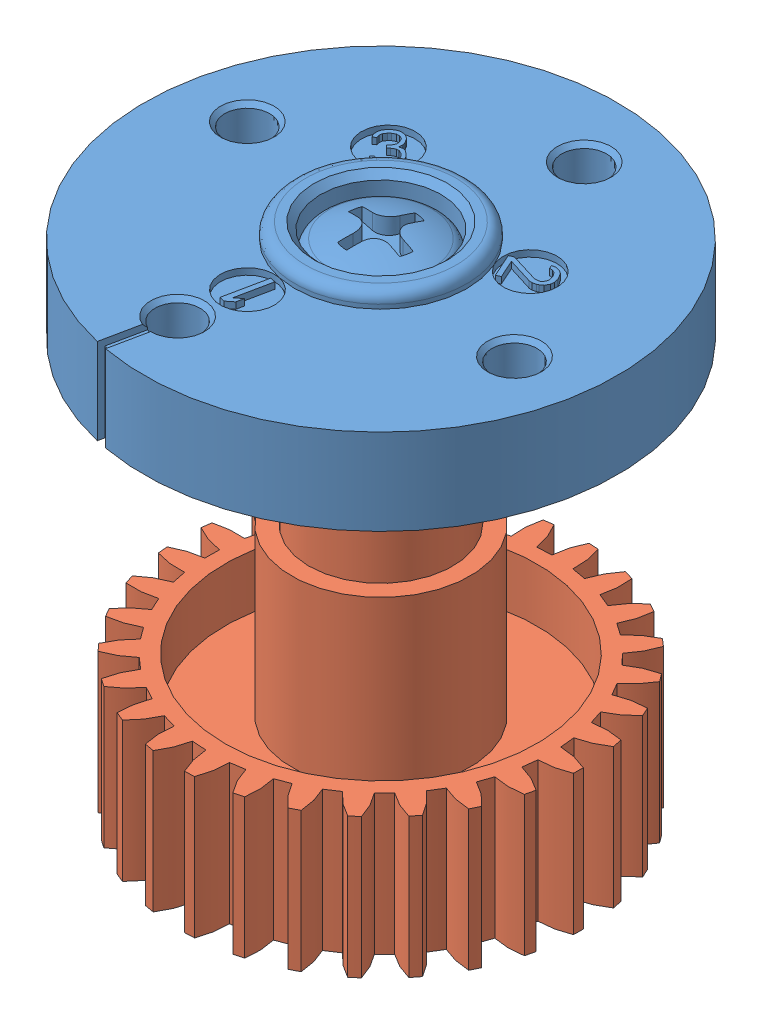
SolidWorks assembly AX-12A couvercle avec roue et pignons, configuration Défaut. Lengths in mm.
Overall size (26 27.3 26).
2 component instances, 2 part files, 3 mates.
Components (placement in the parent):
- 9_ALL_COMPONENTS_1-1-1: 9_ALL_COMPONENTS_1-1 [Défaut] at (-30.6939 -9.3809 23.3706) x (0.97926 0 0.202606) z (-0.202606 0 0.97926) size (22 9.8 22)
- 6ème Pignon-1: 6ème Pignon [Défaut] at (-27.767 -14.8019 29.0568) x (0 -1 0) z (0.889119 0 -0.457676) size (24.5 18.57 18.59)
Mates (geometry in assembly coordinates):
- Coaxiale4: concentric aligned: cylinder of 9_ALL_COMPONENTS_1-1-1 through (-30.6939 -3.3809 23.3706) axis (0 -1 0) radius 4.5; cylinder of 6ème Pignon-1 through (-30.6939 -7.1809 23.3706) axis (0 -1 0) radius 3.35
- Coïncidente5: coincident: plane of 9_ALL_COMPONENTS_1-1-1 through (-32.9099 -2.203 24.7813) normal (0.369575 0 -0.929201); line of 6ème Pignon-1 through (-33.4443 -7.1809 24.5688) axis (0 1 0)
- Distance2: distance = 0.5 mm anti-aligned: plane of 9_ALL_COMPONENTS_1-1-1 through (-28.334 -2.2809 26.9619) normal (0 -1 0); plane of 6ème Pignon-1 through (-29.3637 -2.7809 23.3197) normal (0 1 0)
